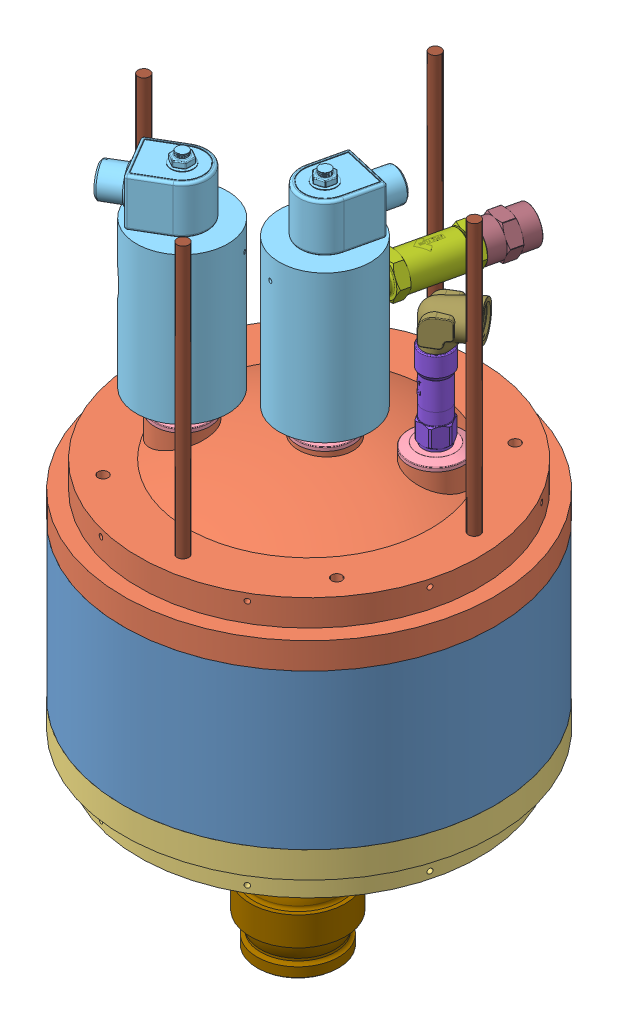
SolidWorks assembly 000054-R02_LNG_TANK_ASSM, configuration Default. Lengths in mm.
Overall size (416.65 551.38 416.65).
24 component instances, 13 part files, 37 mates.
Components (placement in the parent):
- 000056-R02_LNG_TANK_WALL-1: 000056-R02_LNG_TANK_WALL [Default] at origin size (304.8 127 304.8)
- 000052-R02a_TANK_BULKHEAD_TOP-1: 000052-R02a_TANK_BULKHEAD_TOP [Default] at (0 127 0) x (0.864741 0 -0.502217) z (0.502217 0 0.864741) size (304.8 66.04 304.8)
- 000052-R02b_TANK_BULKHEAD_BOTTOM-2: 000052-R02b_TANK_BULKHEAD_BOTTOM [Default] x (-0.502217 0 -0.864741) z (-0.864741 0 0.502217) size (304.8 66.04 304.8)
- FUELTANKPARTS-1-2-AL-FITTING-1: FUELTANKPARTS-1-2-AL-FITTING [Default] at (8.2367 186.182 -4.7836) x (0.997569 0 -0.069681) z (0.069681 0 0.997569) size (44.96 12.45 44.96)
- FUELTANKPARTS-1-2-AL-FITTING-2: FUELTANKPARTS-1-2-AL-FITTING [Default] at (65.8933 183.642 -38.269) x (0.65902 0 -0.752126) z (0.752126 0 0.65902) size (44.96 12.45 44.96)
- FUELTANKPARTS-1-2-AL-FITTING-6: FUELTANKPARTS-1-2-AL-FITTING [Default] at (-38.269 -56.642 -65.8933) x (0.837169 0 0.546944) z (0.546944 0 -0.837169) size (44.96 12.45 44.96)
- FUELTANKPARTS-1-2-AL-FITTING-7: FUELTANKPARTS-1-2-AL-FITTING [Default] at (12.7563 -59.182 21.9644) x (-0.715018 0 -0.699106) z (-0.699106 0 0.715018) size (44.96 12.45 44.96)
- FUELTANKPARTS-1-2-AL-FITTING-11: FUELTANKPARTS-1-2-AL-FITTING [Default] at (-38.269 183.642 -65.8933) x (-0.752126 0 -0.65902) z (0.65902 0 -0.752126) size (44.96 12.45 44.96)
- FUELTANKPARTS-1-2-AL-FITTING-12: FUELTANKPARTS-1-2-AL-FITTING [Default] at (-65.8933 183.642 38.269) x (-0.65902 0 0.752126) z (-0.752126 0 -0.65902) size (44.96 12.45 44.96)
- EH50-08-D024-OXXP-1: EH50-08-D024-OXXP [Default] at (8.2367 285.9278 -4.7836) x (0.224484 0 -0.974478) z (0.974478 0 0.224484) size (87.5 168.84 74.93)
- cryo-pducer-temp-1: cryo-pducer-temp [Default] at (-38.269 185.928 -65.8933) size (25.65 83.82 25.65)
- TIN20021-1: TIN20021 [Default] at (31.1868 285.9278 -104.4093) x (-0.224484 0 0.974478) z (0.974448 -0.007817 0.224477) size (102.11 28.58 33)
- CRVP4-500B-1: CRVP4-500B [Default] at (65.8933 183.642 -38.269) x (0 1 0) z (-0.024117 0 0.999709) size (82.27 25.15 25.15)
- atomatik-2: atomatik [Default] at (12.7563 -128.3301 21.9644) x (0 1 0) z (-0.491272 0 0.871006) size (76.23 180.98 78)
- 44665K173_STANDARD-WALL ALUMINUM THREADED PIPE NIPPLE-1: 44665K173_STANDARD-WALL ALUMINUM THREADED PIPE NIPPLE [44665K173] at (-65.8933 201.6379 38.269) x (1 0 0) z (0 1 0) size (22.19 22.36 51.97)
- 44665K173_STANDARD-WALL ALUMINUM THREADED PIPE NIPPLE-2: 44665K173_STANDARD-WALL ALUMINUM THREADED PIPE NIPPLE [44665K173] at (8.2367 204.1779 -4.7836) x (1 0 0) z (0 1 0) size (22.19 22.36 51.97)
- 44665K173_STANDARD-WALL ALUMINUM THREADED PIPE NIPPLE-3: 44665K173_STANDARD-WALL ALUMINUM THREADED PIPE NIPPLE [44665K173] at (12.7563 -77.1779 21.9644) x (0.980261 0 0.197708) z (0 1 0) size (22.19 22.36 51.97)
- MCMASTER_94435A523_9in-1: MCMASTER_94435A523_9in [Default] at (-16.0544 163.83 -119.5771) x (0 1 0) z (0.780678 0 -0.624933) size (228.6 9.53 9.53)
- MCMASTER_94435A523_9in-3: MCMASTER_94435A523_9in [Default] at (-119.5771 163.83 16.0544) x (0 1 0) z (-0.624933 0 -0.780678) size (228.6 9.53 9.53)
- MCMASTER_94435A523_9in-4: MCMASTER_94435A523_9in [Default] at (16.0544 163.83 119.5771) x (0 1 0) z (-0.780678 0 0.624933) size (228.6 9.53 9.53)
- MCMASTER_94435A523_9in-5: MCMASTER_94435A523_9in [Default] at (119.5771 163.83 -16.0544) x (0 1 0) z (0.624933 0 0.780678) size (228.6 9.53 9.53)
- 3861T240_MED-PRESSURE ANODIZED ALUM THRD PIPE FITTING-2: 3861T240_MED-PRESSURE ANODIZED ALUM THRD PIPE FITTING [3861T24] at (91.3176 286.9406 -53.7479) x (0.520028 0 0.854149) z (0.854149 0 -0.520028) size (30.97 56.51 41.63)
- 51205K223_EXTREME-PRESSURE 316 SS THREADED PIPE FITTING-1: 51205K223_EXTREME-PRESSURE 316 SS THREADED PIPE FITTING [51205K223] at (35.4632 285.9278 -122.9732) x (-0.827824 -0.52758 -0.190701) z (-0.224484 0 0.974478) size (28.7 32.74 38.1)
- EH50-08-D024-OXXP-2: EH50-08-D024-OXXP [Default] at (-65.8933 283.3878 38.269) x (-0.861847 0 0.507168) z (-0.507168 0 -0.861847) size (87.5 168.84 74.93)
Mates (geometry in assembly coordinates):
- Coincident1: coincident anti-aligned: axis of 000056-R02_LNG_TANK_WALL-1 through (127 0 127) axis (0 0 -1); axis of 000052-R02a_TANK_BULKHEAD_TOP-1 through (0 77.1587 0) axis (0 1 0)
- Coincident2: coincident anti-aligned: plane of 000056-R02_LNG_TANK_WALL-1 through (0 127 0) normal (0 1 0); plane of 000052-R02a_TANK_BULKHEAD_TOP-1 through (126.2955 127 -73.3488) normal (0 -1 0)
- Coincident3: coincident aligned: axis of 000056-R02_LNG_TANK_WALL-1 through (127 0 127) axis (0 0 -1); axis of 000052-R02b_TANK_BULKHEAD_BOTTOM-2 through (0 0 0) axis (0 -1 0)
- Coincident4: coincident anti-aligned: plane of 000056-R02_LNG_TANK_WALL-1 through (0 0 0) normal (0 -1 0); plane of 000052-R02b_TANK_BULKHEAD_BOTTOM-2 through (-73.3488 0 -126.2955) normal (0 1 0)
- Coincident10: coincident anti-aligned: plane of 000052-R02a_TANK_BULKHEAD_TOP-1 through (8.2367 193.04 -4.7836) normal (0 1 0); plane of FUELTANKPARTS-1-2-AL-FITTING-1 through (8.2367 193.04 -4.7836) normal (0 -1 0)
- Concentric6: concentric anti-aligned: cylinder of 000052-R02b_TANK_BULKHEAD_BOTTOM-2 through (12.7563 -66.04 21.9644) axis (0 -1 0) radius 12.7; cylinder of FUELTANKPARTS-1-2-AL-FITTING-7 through (12.7563 -66.04 21.9644) axis (0 1 0) radius 12.7
- Coincident11: coincident anti-aligned: plane of 000052-R02b_TANK_BULKHEAD_BOTTOM-2 through (12.7563 -66.04 21.9644) normal (0 -1 0); plane of FUELTANKPARTS-1-2-AL-FITTING-7 through (12.7563 -66.04 21.9644) normal (0 1 0)
- Concentric8: concentric anti-aligned: cylinder of 000052-R02b_TANK_BULKHEAD_BOTTOM-2 through (-38.269 -63.5 -65.8933) axis (0 -1 0) radius 12.7; cylinder of FUELTANKPARTS-1-2-AL-FITTING-6 through (-38.269 -63.5 -65.8933) axis (0 1 0) radius 12.7
- Coincident12: coincident anti-aligned: plane of 000052-R02b_TANK_BULKHEAD_BOTTOM-2 through (-38.269 -63.5 -65.8933) normal (0 -1 0); plane of FUELTANKPARTS-1-2-AL-FITTING-6 through (-38.269 -63.5 -65.8933) normal (0 1 0)
- Concentric11: concentric anti-aligned: cylinder of 000052-R02a_TANK_BULKHEAD_TOP-1 through (-38.269 190.5 -65.8933) axis (0 1 0) radius 12.7; cylinder of 000052-R02b_TANK_BULKHEAD_BOTTOM-2 through (-38.269 -63.5 -65.8933) axis (0 -1 0) radius 12.7
- Concentric12: concentric anti-aligned: cylinder of 000052-R02a_TANK_BULKHEAD_TOP-1 through (65.8933 190.5 -38.269) axis (0 1 0) radius 12.7; cylinder of FUELTANKPARTS-1-2-AL-FITTING-2 through (65.8933 196.088 -38.269) axis (0 -1 0) radius 9.271
- Coincident14: coincident anti-aligned: plane of 000052-R02a_TANK_BULKHEAD_TOP-1 through (65.8933 190.5 -38.269) normal (0 1 0); plane of FUELTANKPARTS-1-2-AL-FITTING-2 through (65.8933 190.5 -38.269) normal (0 -1 0)
- Concentric14: concentric anti-aligned: cylinder of FUELTANKPARTS-1-2-AL-FITTING-1 through (8.2367 198.628 -4.7836) axis (0 -1 0) radius 9.271; cone of EH50-08-D024-OXXP-1 through (8.2367 209.7278 -4.7836) axis (0 1 0)
- Concentric15: concentric aligned: cylinder of FUELTANKPARTS-1-2-AL-FITTING-11 through (-38.269 196.088 -65.8933) axis (0 -1 0) radius 9.271; cylinder of cryo-pducer-temp-1 through (-38.269 185.928 -65.8933) axis (0 -1 0) radius 8.89
- Distance2: distance = 2.54 mm anti-aligned: plane of cryo-pducer-temp-1 through (-26.839 198.628 -65.8933) normal (0 -1 0); plane of FUELTANKPARTS-1-2-AL-FITTING-11 through (-38.269 196.088 -65.8933) normal (0 1 0)
- Concentric16: concentric anti-aligned: cylinder of 000052-R02a_TANK_BULKHEAD_TOP-1 through (8.2367 193.04 -4.7836) axis (0 1 0) radius 12.7; cylinder of FUELTANKPARTS-1-2-AL-FITTING-1 through (8.2367 198.628 -4.7836) axis (0 -1 0) radius 9.271
- Concentric21: concentric aligned: cone of EH50-08-D024-OXXP-1 through (15.8487 285.9278 -37.8272) axis (-0.224484 0 0.974478); cone of TIN20021-1 through (16.9534 285.9278 -42.6228) axis (-0.224484 0 0.974478)
- Distance4: distance = 6.35 mm anti-aligned: plane of EH50-08-D024-OXXP-1 through (15.8487 301.8028 -37.8272) normal (0.224484 0 -0.974478); plane of TIN20021-1 through (9.2361 285.9923 -45.8668) normal (-0.224484 0 0.974478)
- Concentric24: concentric aligned: cylinder of FUELTANKPARTS-1-2-AL-FITTING-2 through (65.8933 196.088 -38.269) axis (0 -1 0) radius 9.271; cone of CRVP4-500B-1 through (65.8933 198.628 -38.269) axis (0 -1 0)
- Distance5: distance = 2.54 mm anti-aligned: plane of CRVP4-500B-1 through (65.8933 198.628 -38.269) normal (0 -1 0); plane of FUELTANKPARTS-1-2-AL-FITTING-2 through (65.8933 196.088 -38.269) normal (0 1 0)
- Concentric36: concentric anti-aligned: cylinder of FUELTANKPARTS-1-2-AL-FITTING-12 through (-65.8933 196.088 38.269) axis (0 -1 0) radius 9.271; cylinder of 44665K173_STANDARD-WALL ALUMINUM THREADED PIPE NIPPLE-1 through (-65.8933 196.088 38.269) axis (0 1 0) radius 10.668
- Coincident36: coincident aligned: plane of FUELTANKPARTS-1-2-AL-FITTING-12 through (-65.8933 196.088 38.269) normal (0 1 0); circle of 44665K173_STANDARD-WALL ALUMINUM THREADED PIPE NIPPLE-1
- Concentric38: concentric anti-aligned: cylinder of FUELTANKPARTS-1-2-AL-FITTING-1 through (8.2367 198.628 -4.7836) axis (0 -1 0) radius 9.271; cylinder of 44665K173_STANDARD-WALL ALUMINUM THREADED PIPE NIPPLE-2 through (8.2367 198.628 -4.7836) axis (0 1 0) radius 10.668
- Coincident38: coincident aligned: plane of FUELTANKPARTS-1-2-AL-FITTING-1 through (8.2367 198.628 -4.7836) normal (0 1 0); circle of 44665K173_STANDARD-WALL ALUMINUM THREADED PIPE NIPPLE-2
- Coincident39: coincident aligned: plane of EH50-08-D024-OXXP-1 through (8.9494 209.7278 -7.8776) normal (0 -1 0); circle of 44665K173_STANDARD-WALL ALUMINUM THREADED PIPE NIPPLE-2
- Concentric39: concentric aligned: cylinder of FUELTANKPARTS-1-2-AL-FITTING-7 through (12.7563 -71.628 21.9644) axis (0 1 0) radius 9.271; cylinder of 44665K173_STANDARD-WALL ALUMINUM THREADED PIPE NIPPLE-3 through (12.7563 -82.7278 21.9644) axis (0 1 0) radius 10.668
- Coincident40: coincident aligned: plane of FUELTANKPARTS-1-2-AL-FITTING-7 through (12.7563 -71.628 21.9644) normal (0 -1 0); circle of 44665K173_STANDARD-WALL ALUMINUM THREADED PIPE NIPPLE-3
- Coincident41: coincident aligned: plane of atomatik-2 through (32.8983 -82.7278 33.3251) normal (0 1 0); circle of 44665K173_STANDARD-WALL ALUMINUM THREADED PIPE NIPPLE-3
- Concentric40: concentric anti-aligned: cylinder of atomatik-2 through (12.7563 -103.6994 21.9644) axis (0 -1 0) radius 16.775; cylinder of 44665K173_STANDARD-WALL ALUMINUM THREADED PIPE NIPPLE-3 through (12.7563 -82.7278 21.9644) axis (0 1 0) radius 10.668
- Concentric41: concentric anti-aligned: cylinder of 000052-R02a_TANK_BULKHEAD_TOP-1 through (-16.0544 170.18 -119.5771) axis (0 1 0) radius 4.2164; cylinder of MCMASTER_94435A523_9in-1 through (-16.0544 392.43 -119.5771) axis (0 -1 0) radius 4.7625
- Distance6: distance = 6.35 mm anti-aligned: plane of MCMASTER_94435A523_9in-1 through (-16.0544 163.83 -119.5771) normal (0 -1 0); plane of 000052-R02a_TANK_BULKHEAD_TOP-1 through (120.8044 170.18 -70.1598) normal (0 1 0)
- Concentric43: concentric anti-aligned: cylinder of CRVP4-500B-1 through (65.8933 236.982 -38.269) axis (0 1 0) radius 7.9375; cylinder of 3861T240_MED-PRESSURE ANODIZED ALUM THRD PIPE FITTING-2 through (65.8933 269.0813 -38.269) axis (0 -1 0) radius 6.7469
- Coincident43: coincident anti-aligned: plane of CRVP4-500B-1 through (65.8933 265.9126 -38.269) normal (0 1 0); plane of 3861T240_MED-PRESSURE ANODIZED ALUM THRD PIPE FITTING-2 through (42.7961 265.9126 -41.8632) normal (0 -1 0)
- Concentric44: concentric anti-aligned: cylinder of TIN20021-1 through (33.4391 285.9278 -114.1863) axis (0.224484 0 -0.974478) radius 5.2388; cylinder of 51205K223_EXTREME-PRESSURE 316 SS THREADED PIPE FITTING-1 through (31.1868 285.9278 -104.4093) axis (-0.224484 0 0.974478) radius 6.35
- Coincident44: coincident anti-aligned: plane of TIN20021-1 through (23.1487 285.9923 -106.261) normal (0.224484 0 -0.974478); plane of 51205K223_EXTREME-PRESSURE 316 SS THREADED PIPE FITTING-1 through (31.1868 285.9278 -104.4093) normal (-0.224484 0 0.974478)
- Concentric45: concentric aligned: cylinder of 44665K173_STANDARD-WALL ALUMINUM THREADED PIPE NIPPLE-1 through (-65.8933 196.088 38.269) axis (0 1 0) radius 10.668; cone of EH50-08-D024-OXXP-2 through (-65.8933 207.1878 38.269) axis (0 1 0)
- Coincident46: coincident aligned: circle of 44665K173_STANDARD-WALL ALUMINUM THREADED PIPE NIPPLE-1; plane of EH50-08-D024-OXXP-2 through (-68.6297 207.1878 39.8792) normal (0 -1 0)
